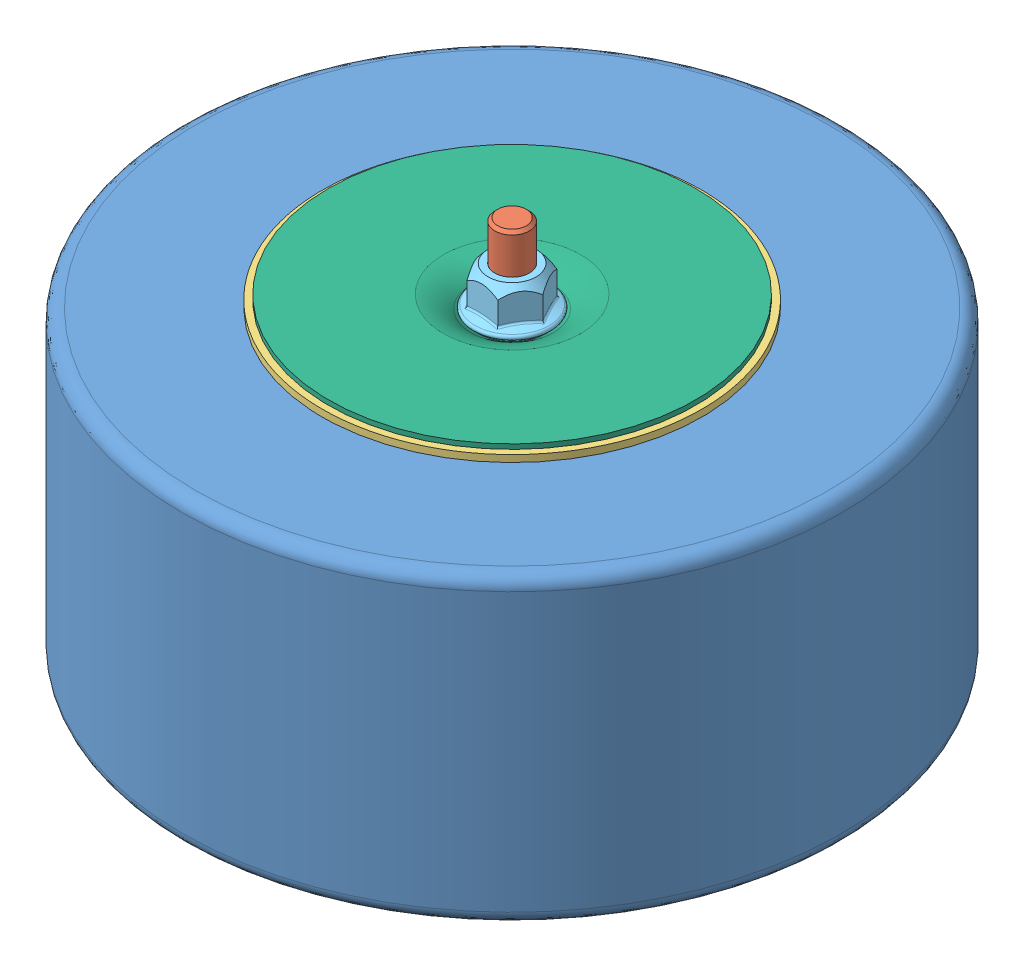
SolidWorks assembly TXFRMR1, configuration Default. Lengths in mm.
Overall size (152 98 152).
6 component instances, 6 part files, 10 mates.
Components (placement in the parent):
- TXFRMR1-1: TXFRMR1 [Default] at origin size (152 70 152)
- socket head cap screw_am-7: socket head cap screw_am [B18.3.1M - 8 x 1.25 x 90 Hex SHCS -- 28NHX] at (0 -45 0) x (0 1 0) z (0.926042 0 -0.37742) size (98 13 13)
- TXFRMR1 Mount (Rubber)-1: TXFRMR1 Mount (Rubber) [Default] at (0 35.8 0) size (88.56 9.74 88.56)
- internal tooth lock washer_am-1: internal tooth lock washer_am [B18.21.2M-Internal Tooth Lock Washers_AM8] at (0 33.8 0) x (1 0 0) z (0 1 0) size (14.75 14.75 0.7)
- prevailing torque hex flange nut_am-1: prevailing torque hex flange nut_am [AM-M8-N] at (0 43.9 0) x (0.837169 0 0.546944) z (0 1 0) size (17.9 17.9 9.4)
- TXFRMR1 Mount-1: TXFRMR1 Mount [Default] at (0 32.7 0) size (84.6 5 84.6)
Mates (geometry in assembly coordinates):
- Distance1: distance = 2 mm anti-aligned: plane of socket head cap screw_am-7 through (2.4532 -37 6.0193) normal (0 1 0); plane of TXFRMR1-1 through (0 -35 0) normal (0 -1 0)
- Concentric12: concentric aligned: cylinder of socket head cap screw_am-7 through (0 -76.75 0) axis (0 -1 0) radius 4; cylinder of TXFRMR1-1 through (0 35 0) axis (0 -1 0) radius 26
- Concentric13: concentric anti-aligned: cylinder of socket head cap screw_am-7 through (0 -76.75 0) axis (0 -1 0) radius 4; cylinder of TXFRMR1 Mount (Rubber)-1 through (0 37.7 0) axis (0 1 0) radius 4.1
- Tangent1: tangent: plane of TXFRMR1-1 through (0 35 0) normal (0 1 0); face of TXFRMR1 Mount (Rubber)-1
- Concentric14: concentric aligned: cylinder of socket head cap screw_am-7 through (0 -76.75 0) axis (0 -1 0) radius 4; cylinder of internal tooth lock washer_am-1 through (0 38.4 0) axis (0 -1 0) radius 7.375
- Coincident1: coincident anti-aligned: plane of TXFRMR1 Mount-1 through (0 33.8 0) normal (0 1 0); plane of internal tooth lock washer_am-1 through (0 33.8 0) normal (0 -1 0)
- Concentric15: concentric anti-aligned: cylinder of socket head cap screw_am-7 through (0 -76.75 0) axis (0 -1 0) radius 4; cylinder of prevailing torque hex flange nut_am-1 through (0 22.7625 0) axis (0 1 0) radius 4
- Coincident2: coincident anti-aligned: plane of internal tooth lock washer_am-1 through (0 38.4 0) normal (0 1 0); plane of prevailing torque hex flange nut_am-1 through (-10.8832 38.4 -7.1103) normal (0 -1 0)
- Tangent2: tangent: face of TXFRMR1 Mount (Rubber)-1; plane of TXFRMR1 Mount-1 through (42.3 36.6 0) normal (0 -1 0)
- Concentric16: concentric anti-aligned: cylinder of socket head cap screw_am-7 through (0 -76.75 0) axis (0 -1 0) radius 4; cylinder of TXFRMR1 Mount-1 through (0 33.8 0) axis (0 1 0) radius 4.1
